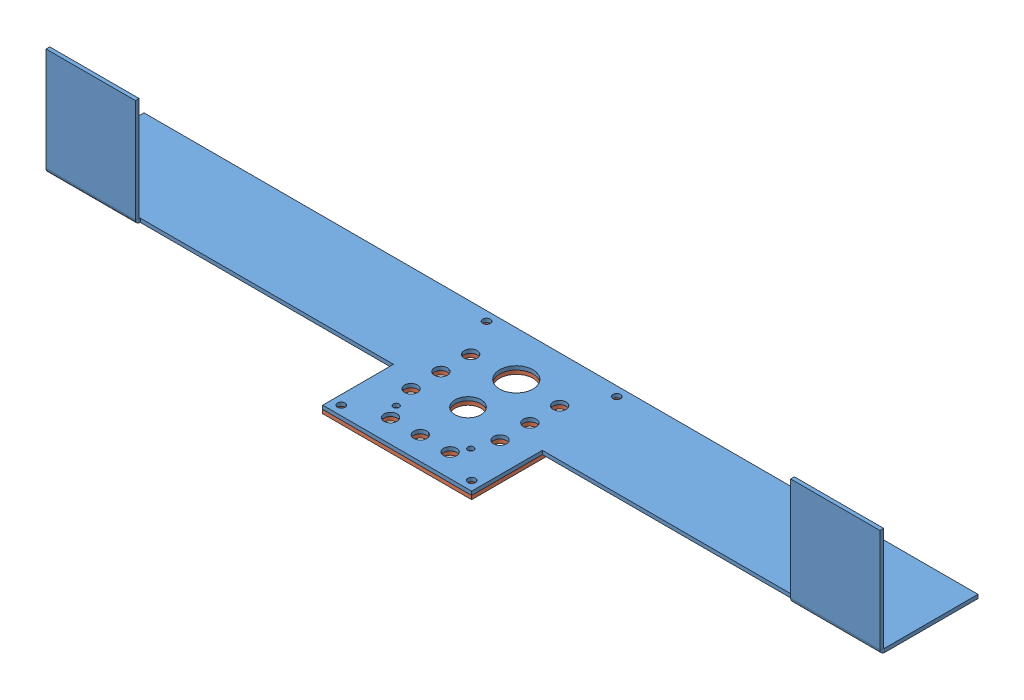
SolidWorks assembly working_interiorwall, configuration Default. Lengths in mm.
Overall size (711.2 95.25 139.7).
2 component instances, 2 part files, 3 mates.
Components (placement in the parent):
- interior wheel well-1: interior wheel well [Default] at (166.5726 449.5375 544.8347) size (711.2 92.07 139.7)
- 3CIM TB Special Shaft Plate-1: 3CIM TB Special Shaft Plate [Default] at (415.898 442.19 591.4621) x (1 0 0) z (0 -1 0) size (127 139.7 3.17)
Mates (geometry in assembly coordinates):
- Coincident1: coincident anti-aligned: plane of interior wheel well-1 through (60.298 445.365 553.3621) normal (0 -1 0); plane of 3CIM TB Special Shaft Plate-1 through (479.398 445.365 693.0621) normal (0 1 0)
- Coincident3: coincident aligned: line of interior wheel well-1 through (352.398 445.365 693.0621) axis (1 0 0); line of 3CIM TB Special Shaft Plate-1 through (352.398 445.365 693.0621) axis (1 0 0)
- Coincident4: coincident aligned: line of interior wheel well-1 through (479.398 445.365 693.0621) axis (0 0 -1); line of 3CIM TB Special Shaft Plate-1 through (479.398 445.365 693.0621) axis (0 0 -1)
